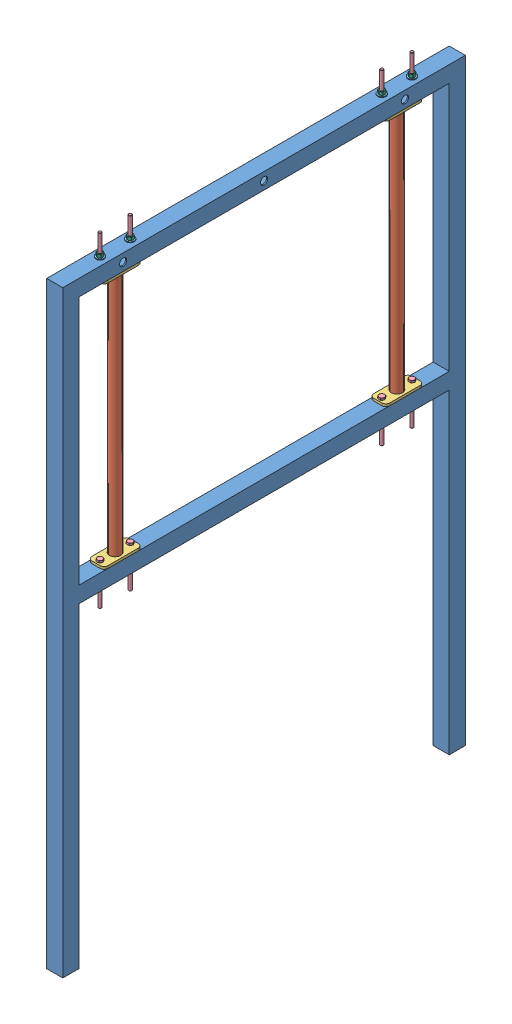
SolidWorks assembly Side frame sub asm, configuration Default. Lengths in mm.
Overall size (40 1539 1000).
31 component instances, 6 part files, 28 mates.
Components (placement in the parent):
- Side frame-1: Side frame [Default] at (665 0 0) x (0 0 -1) z (1 0 0) size (1000 1485 40)
- Slider rod-1: Slider rod [Default] at (343.5 40 -330) x (1 0 0) z (0 -1 0) size (27 27 620)
- Slider rod plate-1: Slider rod plate [Default] at (711 -574 -2.5) x (0 0 -1) z (0 -1 0) size (95 40 6)
- Slider rod plate-2: Slider rod plate [Default] at (711 40 -2.5) x (0 0 -1) z (0 -1 0) size (95 40 6)
- Slider rod plate-3: Slider rod plate [Default] at (711 -580 2.5) x (0 0 1) z (0 1 0) size (95 40 6)
- Slider rod plate-4: Slider rod plate [Default] at (711 34 2.5) x (0 0 1) z (0 1 0) size (95 40 6)
- Slider rod-2: Slider rod [Default] at (343.5 -580 330) x (1 0 0) z (0 1 0) size (27 27 620)
- hex bolt gradeab_iso-1: hex bolt gradeab_iso [ISO 4014 - M8 x 100 x 100-N] at (691 28.7 -312.5) x (0 1 0) z (0 0 1) size (105.3 15.01 13)
- hex bolt gradeab_iso-2: hex bolt gradeab_iso [ISO 4014 - M8 x 100 x 100-N] at (691 28.7 -387.5) x (0 1 0) z (0 0 1) size (105.3 15.01 13)
- hex bolt gradeab_iso-3: hex bolt gradeab_iso [ISO 4014 - M8 x 100 x 100-N] at (691 -568.7 -312.5) x (0 -1 0) z (0 0 1) size (105.3 15.01 13)
- hex bolt gradeab_iso-4: hex bolt gradeab_iso [ISO 4014 - M8 x 100 x 100-N] at (691 -568.7 -387.5) x (0 -1 0) z (0 0 1) size (105.3 15.01 13)
- plain washer 10669 type nl_iso-1: plain washer 10669 type nl_iso [ISO 10669-8.8-N] at (691 80 -312.5) x (0 1 0) z (0 0 1) size (2 20 20)
- plain washer 10669 type nl_iso-2: plain washer 10669 type nl_iso [ISO 10669-8.8-N] at (691 80 -387.5) x (0 1 0) z (0 0 1) size (2 20 20)
- plain washer 10669 type nl_iso-3: plain washer 10669 type nl_iso [ISO 10669-8.8-N] at (691 -620 -312.5) x (0 -1 0) z (0 0 1) size (2 20 20)
- plain washer 10669 type nl_iso-4: plain washer 10669 type nl_iso [ISO 10669-8.8-N] at (691 -620 -387.5) x (0 -1 0) z (0 0 1) size (2 20 20)
- hex nut gradec_iso-1: hex nut gradec_iso [ISO - 4034 - M8 - N] at (691 -629.9 -387.5) x (1 0 0) z (0 -1 0) size (13 15.01 7.9)
- hex nut gradec_iso-2: hex nut gradec_iso [ISO - 4034 - M8 - N] at (691 -629.9 -312.5) x (1 0 0) z (0 -1 0) size (13 15.01 7.9)
- hex nut gradec_iso-3: hex nut gradec_iso [ISO - 4034 - M8 - N] at (691 89.9 -312.5) x (1 0 0) z (0 1 0) size (13 15.01 7.9)
- hex nut gradec_iso-4: hex nut gradec_iso [ISO - 4034 - M8 - N] at (691 89.9 -387.5) x (1 0 0) z (0 1 0) size (13 15.01 7.9)
- hex bolt gradeab_iso-5: hex bolt gradeab_iso [ISO 4014 - M8 x 100 x 100-N] at (691 28.7 387.5) x (0 1 0) z (0 0 1) size (105.3 15.01 13)
- hex bolt gradeab_iso-6: hex bolt gradeab_iso [ISO 4014 - M8 x 100 x 100-N] at (691 -568.7 312.5) x (0 -1 0) z (0 0 1) size (105.3 15.01 13)
- hex bolt gradeab_iso-7: hex bolt gradeab_iso [ISO 4014 - M8 x 100 x 100-N] at (691 -568.7 387.5) x (0 -1 0) z (0 0 1) size (105.3 15.01 13)
- plain washer 10669 type nl_iso-5: plain washer 10669 type nl_iso [ISO 10669-8.8-N] at (691 80 312.5) x (0 1 0) z (0 0 1) size (2 20 20)
- plain washer 10669 type nl_iso-6: plain washer 10669 type nl_iso [ISO 10669-8.8-N] at (691 80 387.5) x (0 1 0) z (0 0 1) size (2 20 20)
- plain washer 10669 type nl_iso-7: plain washer 10669 type nl_iso [ISO 10669-8.8-N] at (691 -620 312.5) x (0 -1 0) z (0 0 1) size (2 20 20)
- plain washer 10669 type nl_iso-8: plain washer 10669 type nl_iso [ISO 10669-8.8-N] at (691 -620 387.5) x (0 -1 0) z (0 0 1) size (2 20 20)
- hex nut gradec_iso-5: hex nut gradec_iso [ISO - 4034 - M8 - N] at (691 -622 387.5) x (1 0 0) z (0 1 0) size (13 15.01 7.9)
- hex nut gradec_iso-6: hex nut gradec_iso [ISO - 4034 - M8 - N] at (691 -622 312.5) x (1 0 0) z (0 1 0) size (13 15.01 7.9)
- hex nut gradec_iso-7: hex nut gradec_iso [ISO - 4034 - M8 - N] at (691 82 387.5) x (1 0 0) z (0 -1 0) size (13 15.01 7.9)
- hex bolt gradeab_iso-8: hex bolt gradeab_iso [ISO 4014 - M8 x 100 x 100-N] at (691 28.7 312.5) x (0 1 0) z (0 0 1) size (105.3 15.01 13)
- hex nut gradec_iso-8: hex nut gradec_iso [ISO - 4034 - M8 - N] at (691 82 312.5) x (1 0 0) z (0 -1 0) size (13 15.01 7.9)
Mates (geometry in assembly coordinates):
- Coincident17: coincident: plane of Side frame-1 through (711 40 0) normal (0 -1 0); plane of Slider rod-1 through (691 40 -350) normal (0 1 0)
- Coincident19: coincident: plane of Side frame-1 through (711 -580 0) normal (0 1 0); plane of Slider rod plate-1 through (711 -580 -2.5) normal (0 -1 0)
- Coincident21: coincident: plane of Side frame-1 through (711 0 0) normal (1 0 0); plane of Slider rod plate-1 through (711 -580 -397.5) normal (1 0 0)
- Concentric2: concentric: cylinder of Slider rod-1 through (691 -580 -350) axis (0 1 0) radius 13.5; cylinder of Slider rod plate-1 through (691 -580 -350) axis (0 1 0) radius 14
- Concentric3: concentric: cylinder of Slider rod plate-2 through (691 34 -312.5) axis (0 1 0) radius 4.25; cylinder of hex bolt gradeab_iso-1 through (691 28.7 -312.5) axis (0 -1 0) radius 6.5
- Coincident22: coincident: plane of Slider rod plate-2 through (711 34 -2.5) normal (0 -1 0); plane of hex bolt gradeab_iso-1 through (683.4944 34 -312.5) normal (0 1 0)
- Concentric4: concentric: cylinder of Slider rod plate-2 through (691 34 -387.5) axis (0 1 0) radius 4.25; cylinder of hex bolt gradeab_iso-2 through (691 28.7 -387.5) axis (0 -1 0) radius 6.5
- Coincident23: coincident: plane of Slider rod plate-2 through (711 34 -2.5) normal (0 -1 0); plane of hex bolt gradeab_iso-2 through (683.4944 34 -387.5) normal (0 1 0)
- Concentric5: concentric: cylinder of Slider rod plate-1 through (691 -580 -312.5) axis (0 1 0) radius 4.25; cylinder of hex bolt gradeab_iso-3 through (691 -568.7 -312.5) axis (0 1 0) radius 6.5
- Coincident24: coincident: plane of Slider rod plate-1 through (711 -574 -2.5) normal (0 1 0); plane of hex bolt gradeab_iso-3 through (698.5056 -574 -312.5) normal (0 -1 0)
- Concentric6: concentric: cylinder of Slider rod plate-1 through (691 -580 -387.5) axis (0 1 0) radius 4.25; cylinder of hex bolt gradeab_iso-4 through (691 -568.7 -387.5) axis (0 1 0) radius 6.5
- Coincident25: coincident: plane of Slider rod plate-1 through (711 -574 -2.5) normal (0 1 0); plane of hex bolt gradeab_iso-4 through (698.5056 -574 -387.5) normal (0 -1 0)
- Concentric7: concentric: cylinder of Side frame-1 through (691 -1405 -312.5) axis (0 1 0) radius 5; cylinder of plain washer 10669 type nl_iso-1 through (691 82 -312.5) axis (0 -1 0) radius 4.4
- Coincident26: coincident: plane of Side frame-1 through (711 80 0) normal (0 1 0); plane of plain washer 10669 type nl_iso-1 through (691 80 -312.5) normal (0 -1 0)
- Concentric8: concentric: cylinder of Side frame-1 through (691 -1405 -387.5) axis (0 1 0) radius 5; cylinder of plain washer 10669 type nl_iso-2 through (691 82 -387.5) axis (0 -1 0) radius 4.4
- Coincident27: coincident: plane of Side frame-1 through (711 80 0) normal (0 1 0); plane of plain washer 10669 type nl_iso-2 through (691 80 -387.5) normal (0 -1 0)
- Concentric9: concentric: cylinder of Side frame-1 through (691 -1405 -312.5) axis (0 1 0) radius 5; cylinder of plain washer 10669 type nl_iso-3 through (691 -622 -312.5) axis (0 1 0) radius 4.4
- Coincident28: coincident: plane of Side frame-1 through (711 -620 0) normal (0 -1 0); plane of plain washer 10669 type nl_iso-3 through (691 -620 -312.5) normal (0 1 0)
- Concentric10: concentric: cylinder of Side frame-1 through (691 -1405 -387.5) axis (0 1 0) radius 5; cylinder of plain washer 10669 type nl_iso-4 through (691 -622 -387.5) axis (0 1 0) radius 4.4
- Coincident29: coincident: plane of Side frame-1 through (711 -620 0) normal (0 -1 0); plane of plain washer 10669 type nl_iso-4 through (691 -620 -387.5) normal (0 1 0)
- Concentric11: concentric: cylinder of plain washer 10669 type nl_iso-4 through (691 -622 -387.5) axis (0 1 0) radius 4.4; cylinder of hex nut gradec_iso-1 through (691 -604.8625 -387.5) axis (0 -1 0) radius 4
- Coincident30: coincident: plane of plain washer 10669 type nl_iso-4 through (691 -622 -387.5) normal (0 -1 0); plane of hex nut gradec_iso-1 through (691 -622 -379.9944) normal (0 1 0)
- Concentric12: concentric: cylinder of plain washer 10669 type nl_iso-3 through (691 -622 -312.5) axis (0 1 0) radius 4.4; cylinder of hex nut gradec_iso-2 through (691 -604.8625 -312.5) axis (0 -1 0) radius 4
- Coincident31: coincident: plane of plain washer 10669 type nl_iso-3 through (691 -622 -312.5) normal (0 -1 0); plane of hex nut gradec_iso-2 through (691 -622 -304.9944) normal (0 1 0)
- Concentric13: concentric: cylinder of plain washer 10669 type nl_iso-1 through (691 82 -312.5) axis (0 -1 0) radius 4.4; cylinder of hex nut gradec_iso-3 through (691 64.8625 -312.5) axis (0 1 0) radius 4
- Coincident32: coincident: plane of plain washer 10669 type nl_iso-1 through (691 82 -312.5) normal (0 1 0); plane of hex nut gradec_iso-3 through (691 82 -320.0056) normal (0 -1 0)
- Concentric14: concentric: cylinder of plain washer 10669 type nl_iso-2 through (691 82 -387.5) axis (0 -1 0) radius 4.4; cylinder of hex nut gradec_iso-4 through (691 64.8625 -387.5) axis (0 1 0) radius 4
- Coincident33: coincident: plane of plain washer 10669 type nl_iso-2 through (691 82 -387.5) normal (0 1 0); plane of hex nut gradec_iso-4 through (691 82 -395.0056) normal (0 -1 0)
